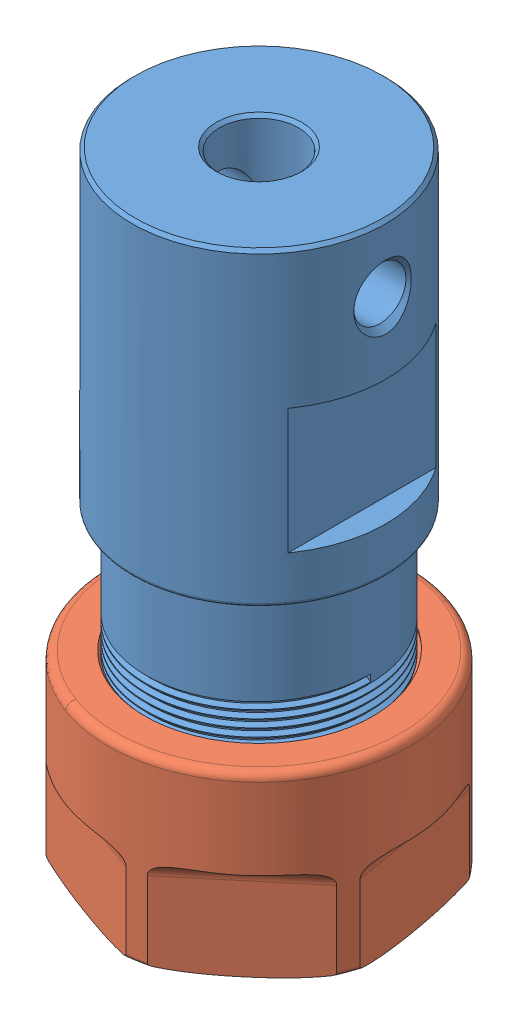
SolidWorks assembly ER11 collet, configuration Default. Lengths in mm.
Overall size (24.42 39.8 24.39).
2 component instances, 2 part files, 2 mates.
Components (placement in the parent):
- ER11 - Collet Chuck-1: ER11 - Collet Chuck [Default] at origin size (16 35.39 16)
- ER11 - Nut - Type A-1: ER11 - Nut - Type A [M14x0.75] at (0 7.5 0) x (-0.938941 0 -0.344078) z (-0.344078 0 0.938941) size (19.04 12.71 19)
Mates (geometry in assembly coordinates):
- Концентричный1: concentric anti-aligned: cylinder of ER11 - Collet Chuck-1 through (0 34.8 0) axis (0 -1 0) radius 8; cylinder of ER11 - Nut - Type A-1 through (0 -3.8723 0) axis (0 1 0) radius 9.5
- Совпадение1: coincident anti-aligned: plane of ER11 - Collet Chuck-1 through (-6.831 0 -6.831) normal (0 -1 0); plane of ER11 - Nut - Type A-1 through (9.0889 0 -4.214) normal (0 1 0)
